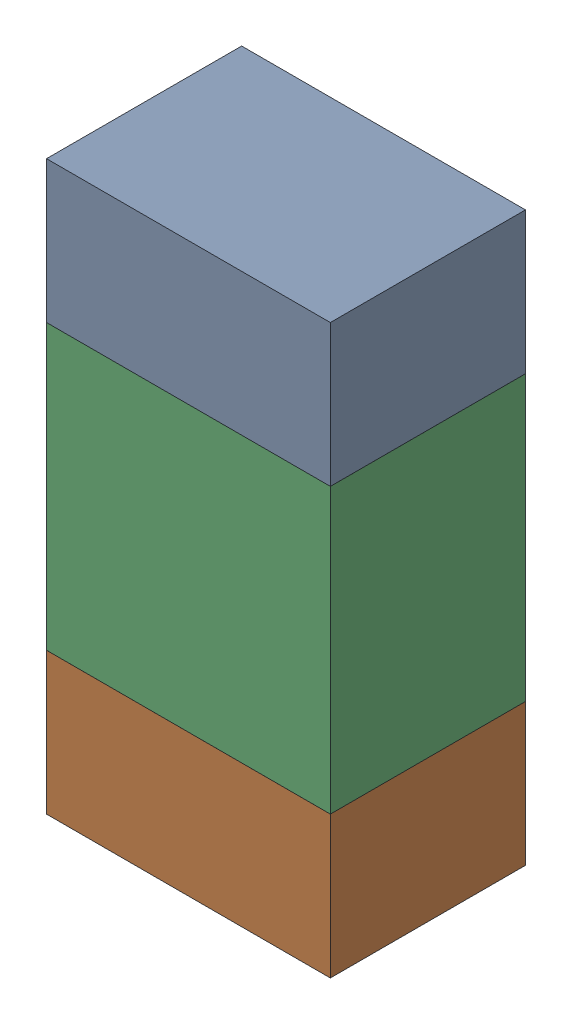
SolidWorks assembly R56, configuration ﾃﾞﾌｫﾙﾄ. Lengths in mm.
Overall size (0.8 1.6 0.55).
6 component instances, 2 part files, 0 mates.
Components (placement in the parent):
- 689261784-1: 689261784 [ﾃﾞﾌｫﾙﾄ] at (79.7501 17.0999 0) size (0.8 0.4 0.55)
  - Extruded_34-1: Extruded_34 [ﾃﾞﾌｫﾙﾄ] at origin size (0.8 0.4 0.55)
- 689261784-2: 689261784 [ﾃﾞﾌｫﾙﾄ] at (79.7501 15.8999 0) size (0.8 0.4 0.55)
  - Extruded_34-1: Extruded_34 [ﾃﾞﾌｫﾙﾄ] at origin size (0.8 0.4 0.55)
- 689261648-1: 689261648 [ﾃﾞﾌｫﾙﾄ] at (79.7501 16.5 0) size (0.8 0.8 0.55)
  - Extruded_33-1: Extruded_33 [ﾃﾞﾌｫﾙﾄ] at origin size (0.8 0.8 0.55)
